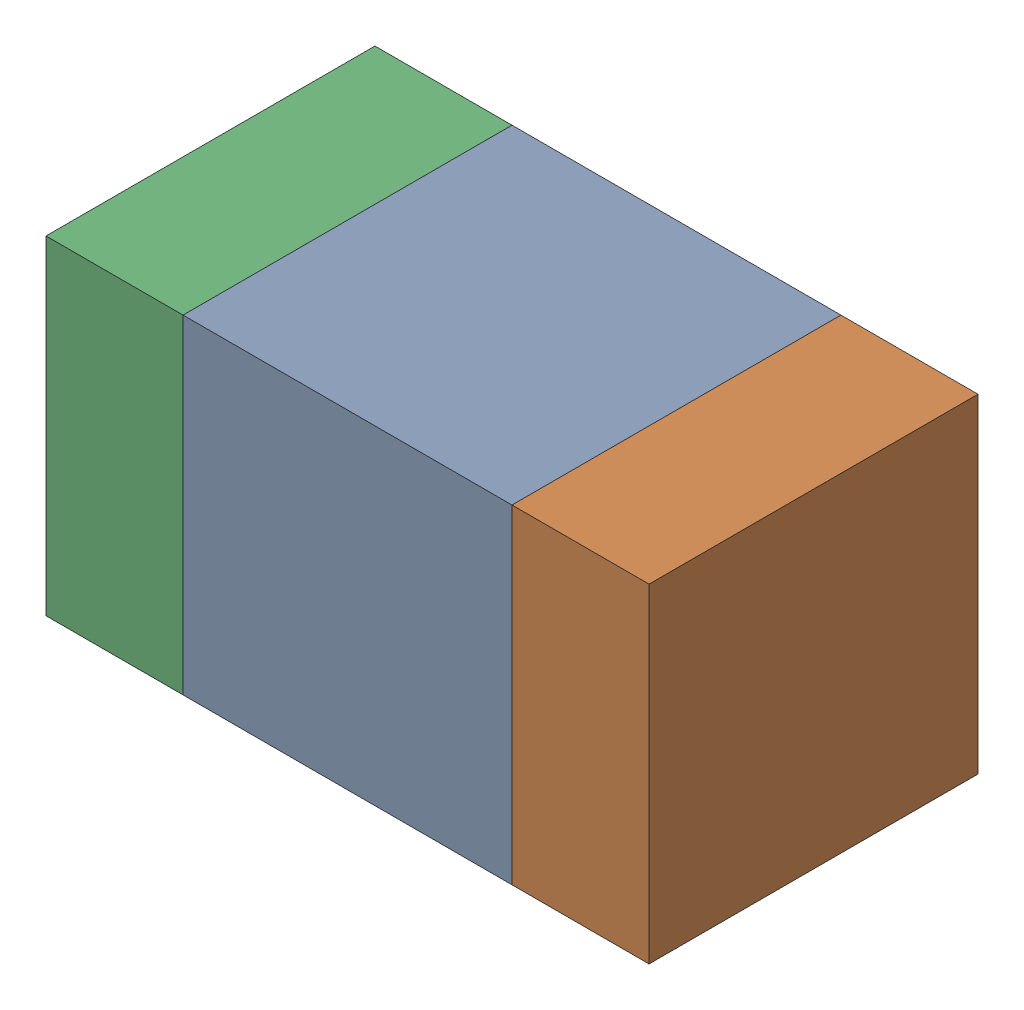
SolidWorks assembly C125_1PCB, configuration Default. Lengths in mm.
Overall size (1.1 0.6 0.6).
6 component instances, 2 part files, 0 mates.
Components (placement in the parent):
- 761606048-1: 761606048 [Default] at (105.8 104.5 0) size (0.6 0.6 0.6)
  - Extruded_9-1: Extruded_9 [Default] at origin size (0.6 0.6 0.6)
- 854785160-1: 854785160 [Default] at (106.225 104.5 0) size (0.25 0.6 0.6)
  - Extruded_19-1: Extruded_19 [Default] at origin size (0.25 0.6 0.6)
- 854785160-2: 854785160 [Default] at (105.375 104.5 0) size (0.25 0.6 0.6)
  - Extruded_19-1: Extruded_19 [Default] at origin size (0.25 0.6 0.6)
